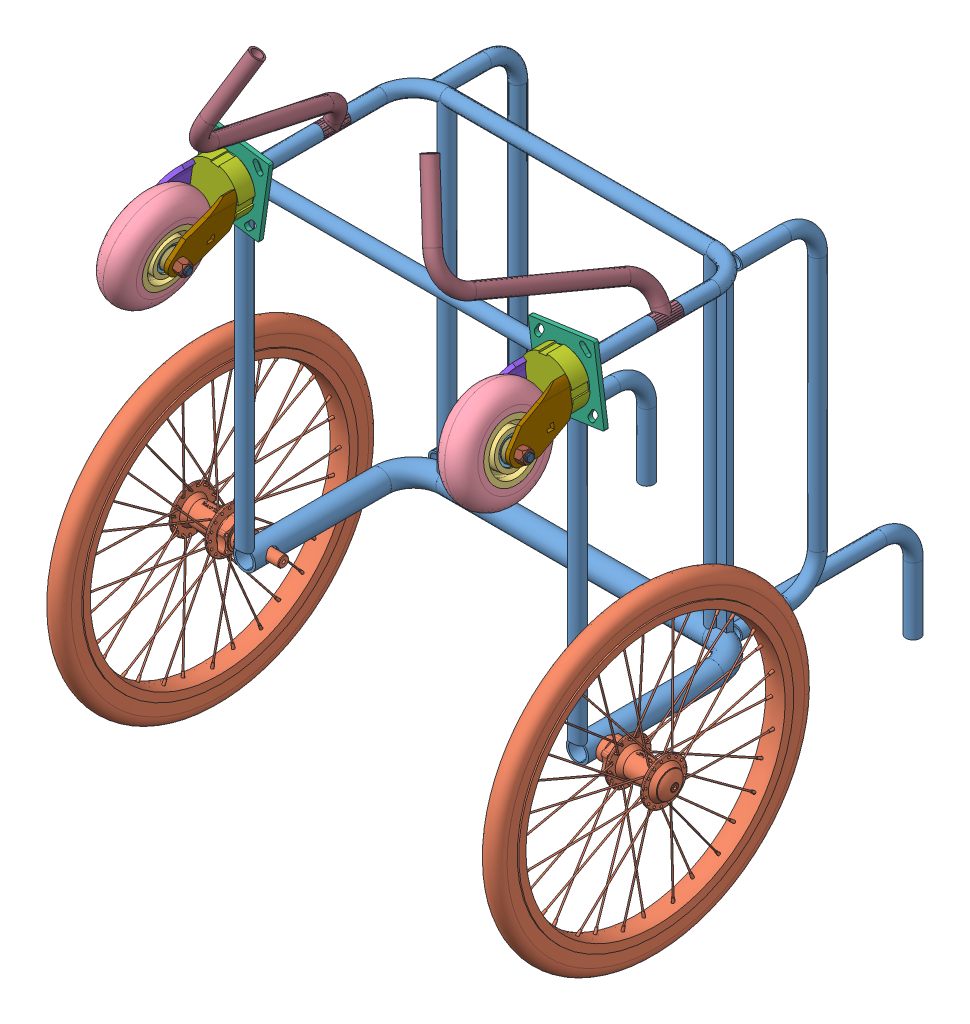
SolidWorks assembly Assem1, configuration Default. Lengths in mm.
Overall size (741.4 1014.78 794.46).
31 component instances, 13 part files, 5 mates.
Components (placement in the parent):
- toiframe-1: toiframe [Default<As Machined>] at (84.6787 213.1461 518.8053) size (533.4 660.67 575.34)
- 20 inch wheel-1: 20 inch wheel [Default] at (566.1548 152.8625 747.0682) size (154 478.75 478.75)
- caster-1: caster [По умолчанию] at (532.9543 652.8625 783.4733) x (-0.141049 0.990003 0) z (0.990003 0.141049 0) size (204.75 219.13 103)
  - Masa Central-1: Masa Central [По умолчанию] at (-34.3013 116.75 0) x (0.807021 0.590523 0) z (0 0 1) size (85 85 50)
  - Hule Rueda-1: Hule Rueda [По умолчанию] at (-34.3013 116.75 0) x (-0.450987 0.892531 0) z (0 0 1) size (152.4 152.4 50)
  - radial ball bearing 200k_tfm-1: radial ball bearing 200k_tfm [TOR - 203K - 11,SI,NC,11] at (-34.3013 116.75 -17) x (0 0 -1) z (0.923668 0.383193 0) size (12 40 40)
  - radial ball bearing 200k_tfm-2: radial ball bearing 200k_tfm [TOR - 203K - 11,SI,NC,11] at (-34.3013 116.75 17) x (0 0 -1) z (0.923668 0.383193 0) size (12 40 40)
  - Horquilla Giro-2: Horquilla Giro [По умолчанию] at origin size (110 16.35 100)
  - Horquilla giro base-1: Horquilla giro base [По умолчанию] at (0 10.35 0) size (79.09 25.4 79.09)
  - Horquilla giro der-1: Horquilla giro der [По умолчанию] at (-0.3474 10.35 -67.6363) x (0.999999 0 -0.001362) z (0.001362 0 0.999999) size (74.19 96.77 11.18)
  - Horquilla giro izq-2: Horquilla giro izq [По умолчанию] at (-0.2553 10.35 -0.0136) x (0.999999 0 0.001362) z (-0.001362 0 0.999999) size (74.19 96.77 11.18)
  - heavy hex bolt_am-2: heavy hex bolt_am [B18.2.3.6M - Heavy hex bolt M12 x 1.75 x 90 --90C] at (-34.3013 116.75 -44.95) x (0 0 1) z (-0.982868 -0.184311 0) size (97.95 24.25 21)
  - prevailing torque hex nut_am-1: prevailing torque hex nut_am [AM-M12-N] at (-34.3013 116.75 50.3) size (19.41 22.2 13.3)
  - buje separador-1: buje separador [По умолчанию] at (-34.3013 116.75 23) x (0.923728 0.383049 0) z (0.383049 -0.923728 0) size (30 7.5 30)
  - buje separador-2: buje separador [По умолчанию] at (-34.3013 116.75 -23) x (1 0 0) z (0 1 0) size (30 7.5 30)
- footpeg-1: footpeg [Default<As Machined>] at (532.9543 652.8625 647.1375) x (-0.410375 0.911917 0) z (-0.911917 -0.410375 0) size (307.88 301.91 21.34)
- 20 inch wheel-2: 20 inch wheel [Default] at (-0.2462 152.8625 747.0682) x (-1 0 0) z (0 0 -1) size (154 478.75 478.75)
- caster-2: caster [По умолчанию] at (29.9843 653.2857 783.4733) x (0.141049 0.990003 0) z (0.990003 -0.141049 0) size (204.75 219.13 103)
  - Masa Central-1: Masa Central [По умолчанию] at (-34.3013 116.75 0) x (0.807021 0.590523 0) z (0 0 1) size (85 85 50)
  - Hule Rueda-1: Hule Rueda [По умолчанию] at (-34.3013 116.75 0) x (-0.450987 0.892531 0) z (0 0 1) size (152.4 152.4 50)
  - radial ball bearing 200k_tfm-1: radial ball bearing 200k_tfm [TOR - 203K - 11,SI,NC,11] at (-34.3013 116.75 -17) x (0 0 -1) z (0.923668 0.383193 0) size (12 40 40)
  - radial ball bearing 200k_tfm-2: radial ball bearing 200k_tfm [TOR - 203K - 11,SI,NC,11] at (-34.3013 116.75 17) x (0 0 -1) z (0.923668 0.383193 0) size (12 40 40)
  - Horquilla Giro-2: Horquilla Giro [По умолчанию] at origin size (110 16.35 100)
  - Horquilla giro base-1: Horquilla giro base [По умолчанию] at (0 10.35 0) size (79.09 25.4 79.09)
  - Horquilla giro der-1: Horquilla giro der [По умолчанию] at (-0.3474 10.35 -67.6363) x (0.999999 0 -0.001362) z (0.001362 0 0.999999) size (74.19 96.77 11.18)
  - Horquilla giro izq-2: Horquilla giro izq [По умолчанию] at (-0.2553 10.35 -0.0136) x (0.999999 0 0.001362) z (-0.001362 0 0.999999) size (74.19 96.77 11.18)
  - heavy hex bolt_am-2: heavy hex bolt_am [B18.2.3.6M - Heavy hex bolt M12 x 1.75 x 90 --90C] at (-34.3013 116.75 -44.95) x (0 0 1) z (-0.982868 -0.184311 0) size (97.95 24.25 21)
  - prevailing torque hex nut_am-1: prevailing torque hex nut_am [AM-M12-N] at (-34.3013 116.75 50.3) size (19.41 22.2 13.3)
  - buje separador-1: buje separador [По умолчанию] at (-34.3013 116.75 23) x (0.923728 0.383049 0) z (0.383049 -0.923728 0) size (30 7.5 30)
  - buje separador-2: buje separador [По умолчанию] at (-34.3013 116.75 -23) x (1 0 0) z (0 1 0) size (30 7.5 30)
- footpeg-2: footpeg [Default<As Machined>] at (32.9543 652.8625 647.1375) x (0.410375 0.911917 0) z (-0.911917 0.410375 0) size (307.88 301.91 21.34)
Mates (geometry in assembly coordinates):
- Concentric1: concentric aligned: cylinder of toiframe-1 through (600.9543 152.8625 747.0682) axis (-1 0 0) radius 10; cylinder of 20 inch wheel-1 through (566.1548 152.8625 747.0682) axis (-1 0 0) radius 8
- Tangent1: tangent anti-aligned: cylinder of toiframe-1 through (532.9543 152.8625 772.8053) axis (0 0 -1) radius 16.7005; plane of 20 inch wheel-1 through (549.6548 167.8625 747.0682) normal (-1 0 0)
- Concentric2: concentric anti-aligned: cylinder of toiframe-1 through (532.9543 652.8625 772.8053) axis (0 0 -1) radius 10.668; circle of caster-1/Horquilla Giro-2
- Tangent2: tangent anti-aligned: cylinder of toiframe-1 through (32.9543 652.8625 772.8053) axis (1 0 0) radius 10.668; plane of caster-1/Horquilla Giro-2 through (532.9543 652.8625 783.4733) normal (0 0 -1)
- Concentric3: concentric aligned: cylinder of toiframe-1 through (532.9543 652.8625 772.8053) axis (0 0 -1) radius 10.668; cylinder of footpeg-1 through (532.9543 652.8625 663.4332) axis (0 0 -1) radius 7.8994
